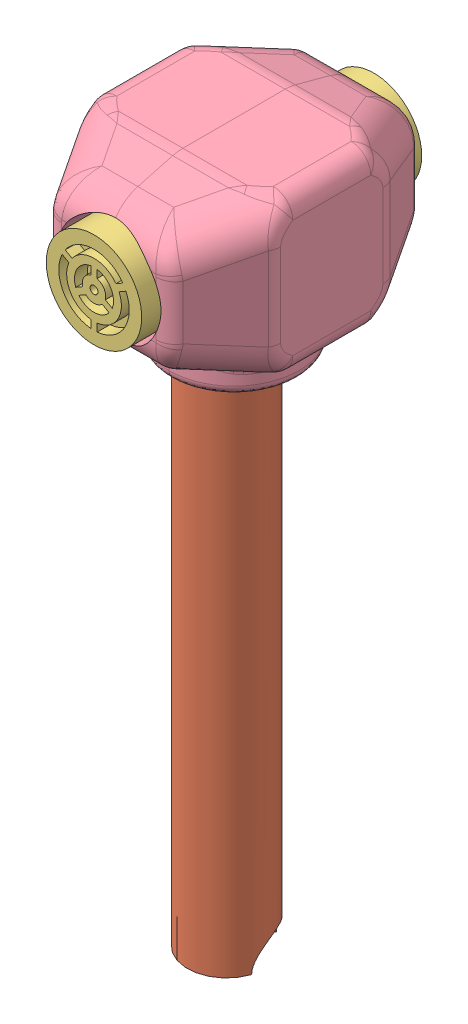
SolidWorks assembly SENSOR, SONAR, TOP ASSY, configuration Default. Lengths in mm.
Overall size (31.75 117.34 45.47).
6 component instances, 4 part files, 16 mates.
Components (placement in the parent):
- SENSOR, SONAR, MOUNTING BLOCK-1: SENSOR, SONAR, MOUNTING BLOCK [Default] at origin size (22.35 20.07 12.7)
- ACUATORS, STEPPER, SHAFT, SONAR-1: ACUATORS, STEPPER, SHAFT, SONAR [Default] at (0 -105.283 0) x (0.44514 0 0.895461) z (-0.895461 0 0.44514) size (12.7 95.79 12.7)
- SENSOR, SONAR, Maxbotix EZ4-1: SENSOR, SONAR, Maxbotix EZ4 [Default] at (1.2065 -1.016 6.35) size (19.94 22.1 16.38)
- SENSOR, SONAR, Maxbotix EZ4-2: SENSOR, SONAR, Maxbotix EZ4 [Default] at (1.2065 -1.016 -6.35) x (-1 0 0) z (0 0 -1) size (19.94 22.1 16.38)
- SENSOR, SONAR, COVER-1: SENSOR, SONAR, COVER [Default] at (1.2065 -1.016 0) size (15.88 31.75 40.64)
- SENSOR, SONAR, COVER-2: SENSOR, SONAR, COVER [Default] at (1.2065 -1.016 0) x (-1 0 0) z (0 0 -1) size (15.88 31.75 40.64)
Mates (geometry in assembly coordinates):
- Coincident1: coincident anti-aligned: plane of SENSOR, SONAR, MOUNTING BLOCK-1 through (11.176 10.033 6.35) normal (0 0 1); plane of SENSOR, SONAR, Maxbotix EZ4-1 through (11.176 10.033 6.35) normal (0 0 -1)
- Coincident2: coincident anti-aligned: plane of SENSOR, SONAR, MOUNTING BLOCK-1 through (11.176 10.033 -6.35) normal (0 0 -1); plane of SENSOR, SONAR, Maxbotix EZ4-2 through (-8.763 10.033 -6.35) normal (0 0 1)
- Coincident3: coincident aligned: plane of SENSOR, SONAR, MOUNTING BLOCK-1 through (-11.176 10.033 6.35) normal (0 1 0); plane of SENSOR, SONAR, Maxbotix EZ4-2 through (11.176 10.033 -7.9375) normal (0 1 0)
- Coincident4: coincident aligned: plane of SENSOR, SONAR, MOUNTING BLOCK-1 through (-11.176 10.033 6.35) normal (0 1 0); plane of SENSOR, SONAR, Maxbotix EZ4-1 through (-8.763 10.033 7.9375) normal (0 1 0)
- Coincident5: coincident aligned: plane of SENSOR, SONAR, MOUNTING BLOCK-1 through (11.176 -10.033 6.35) normal (1 0 0); plane of SENSOR, SONAR, Maxbotix EZ4-1 through (11.176 -12.065 7.9375) normal (1 0 0)
- Coincident6: coincident aligned: plane of SENSOR, SONAR, MOUNTING BLOCK-1 through (11.176 -10.033 6.35) normal (1 0 0); plane of SENSOR, SONAR, Maxbotix EZ4-2 through (11.176 -12.065 -7.9375) normal (1 0 0)
- Concentric1: concentric: cylinder of SENSOR, SONAR, MOUNTING BLOCK-1 through (0 2.667 0) axis (0 -1 0) radius 2.3813; cylinder of ACUATORS, STEPPER, SHAFT, SONAR-1 through (0 -43.0912 0) axis (0 -1 0) radius 5.5563
- Coincident8: coincident aligned: plane of SENSOR, SONAR, MOUNTING BLOCK-1 through (0 0 0) normal (0 1 0); plane of assembly through (0 0 0) normal (0 1 0)
- Coincident9: coincident aligned: plane of SENSOR, SONAR, MOUNTING BLOCK-1 through (0 0 0) normal (0 0 1); plane of assembly through (0 0 0) normal (0 0 1)
- Coincident10: coincident aligned: plane of SENSOR, SONAR, MOUNTING BLOCK-1 through (0 0 0) normal (1 0 0); plane of assembly through (0 0 0) normal (1 0 0)
- Concentric2: concentric anti-aligned: cylinder of SENSOR, SONAR, Maxbotix EZ4-2 through (1.2065 -1.016 -22.733) axis (0 0 1) radius 7.747; cylinder of SENSOR, SONAR, COVER-1 through (1.2065 -1.016 20.32) axis (0 0 -1) radius 8.382
- Concentric4: concentric aligned: cylinder of SENSOR, SONAR, Maxbotix EZ4-2 through (1.2065 -1.016 -22.733) axis (0 0 1) radius 7.747; cylinder of SENSOR, SONAR, COVER-2 through (1.2065 -1.016 -20.32) axis (0 0 1) radius 8.382
- Concentric5: concentric anti-aligned: cylinder of SENSOR, SONAR, COVER-1 through (-8.3185 8.9535 11.1125) axis (1 0 0) radius 0.889; cylinder of SENSOR, SONAR, COVER-2 through (10.7315 8.9535 11.1125) axis (-1 0 0) radius 0.889
- Coincident11: coincident anti-aligned: plane of SENSOR, SONAR, COVER-2 through (1.2065 -1.016 0) normal (0 0 -1); plane of assembly through (0 0 0) normal (0 0 1)
- Parallel1: parallel aligned: plane of SENSOR, SONAR, COVER-2; plane of assembly through (0 0 0) normal (0 1 0)
- Coincident12: coincident anti-aligned: plane of SENSOR, SONAR, MOUNTING BLOCK-1 through (-11.176 -10.033 6.35) normal (0 -1 0); plane of ACUATORS, STEPPER, SHAFT, SONAR-1 through (0 -10.033 0) normal (0 1 0)
